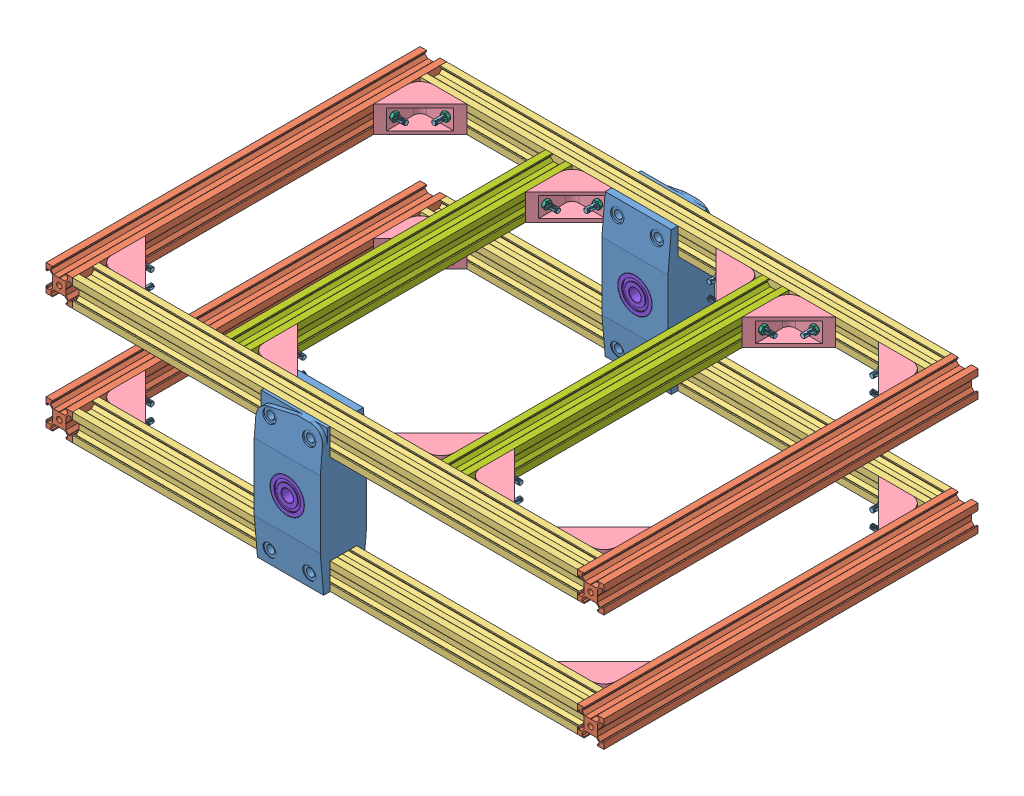
SolidWorks assembly Total Frame, configuration Default. Lengths in mm.
Overall size (422 108 298).
102 component instances, 8 part files, 22 mates.
Components (placement in the parent):
- rocker to body-1: rocker to body [Default] at (-21 0 131.5) size (50 108 35)
- Bottom Frame-1: Bottom Frame [Default] at (-340.2356 -200.3375 -193.6184) size (422 20 283) (flexible)
  - T-slot aluminium profiles(283)-2: T-slot aluminium profiles(283) [Default] at (139.2356 156.3375 52.1184) size (20 20 283)
  - T-slot aluminium profiles(382)-2: T-slot aluminium profiles(382) [Default] at (531.2356 156.3375 325.1184) x (0 0 1) z (-1 0 0) size (20 20 382)
  - T-slot aluminium profiles(382)-3: T-slot aluminium profiles(382) [Default] at (531.2356 156.3375 62.1184) x (0 0 1) z (-1 0 0) size (20 20 382)
  - T-slot aluminium profiles(283)-3: T-slot aluminium profiles(283) [Default] at (541.2356 156.3375 52.1184) size (20 20 283)
  - Connector and Nut-1: Connector and Nut [Default] at (495.0014 140.4658 271.3786) size (38.1 20 38.1) (flexible)
    - connector-1: connector [Default] at (36.2342 15.8717 43.7398) size (35.36 20 35.36)
    - T-bolt-1: T-bolt [Default] at (38.0779 15.8717 18.3844) x (-1 0 0) z (0 0 -1) size (17.8 12.7 9.5)
    - hexagon nut style 1_is-2: hexagon nut style 1_is [IS 1364-3 - M3-W-N] at (28.8342 15.8717 18.3844) x (0 0.996107 0.088148) z (-1 0 0) size (5.5 6.35 2.4)
    - T-bolt-2: T-bolt [Default] at (10.8788 15.8717 45.5835) x (0 0 -1) z (1 0 0) size (17.8 12.7 9.5)
    - hexagon nut style 1_is-3: hexagon nut style 1_is [IS 1364-3 - M3-W-N] at (10.8788 15.8717 36.3398) x (0.175203 0.984532 0) z (0 0 -1) size (5.5 6.35 2.4)
  - Connector and Nut-2: Connector and Nut [Default] at (487.4958 140.4658 108.3525) x (0 0 -1) z (1 0 0) size (38.1 20 38.1) (flexible)
    - connector-1: connector [Default] at (36.2342 15.8717 43.7398) size (35.36 20 35.36)
    - T-bolt-1: T-bolt [Default] at (38.0779 15.8717 18.3844) x (-1 0 0) z (0 0 -1) size (17.8 12.7 9.5)
    - hexagon nut style 1_is-2: hexagon nut style 1_is [IS 1364-3 - M3-W-N] at (28.8342 15.8717 18.3844) x (0 0.996107 0.088148) z (-1 0 0) size (5.5 6.35 2.4)
    - T-bolt-2: T-bolt [Default] at (10.8788 15.8717 45.5835) x (0 0 -1) z (1 0 0) size (17.8 12.7 9.5)
    - hexagon nut style 1_is-3: hexagon nut style 1_is [IS 1364-3 - M3-W-N] at (10.8788 15.8717 36.3398) x (0.175203 0.984532 0) z (0 0 -1) size (5.5 6.35 2.4)
  - Connector and Nut-3: Connector and Nut [Default] at (192.9754 140.4658 278.8842) x (0 0 1) z (-1 0 0) size (38.1 20 38.1) (flexible)
    - connector-1: connector [Default] at (36.2342 15.8717 43.7398) size (35.36 20 35.36)
    - T-bolt-1: T-bolt [Default] at (38.0779 15.8717 18.3844) x (-1 0 0) z (0 0 -1) size (17.8 12.7 9.5)
    - hexagon nut style 1_is-2: hexagon nut style 1_is [IS 1364-3 - M3-W-N] at (28.8342 15.8717 18.3844) x (0 0.996107 0.088148) z (-1 0 0) size (5.5 6.35 2.4)
    - T-bolt-2: T-bolt [Default] at (10.8788 15.8717 45.5835) x (0 0 -1) z (1 0 0) size (17.8 12.7 9.5)
    - hexagon nut style 1_is-3: hexagon nut style 1_is [IS 1364-3 - M3-W-N] at (10.8788 15.8717 36.3398) x (0.175203 0.984532 0) z (0 0 -1) size (5.5 6.35 2.4)
  - Connector and Nut-4: Connector and Nut [Default] at (185.4698 140.4658 115.8582) x (-1 0 0) z (0 0 -1) size (38.1 20 38.1) (flexible)
    - connector-1: connector [Default] at (36.2342 15.8717 43.7398) size (35.36 20 35.36)
    - T-bolt-1: T-bolt [Default] at (38.0779 15.8717 18.3844) x (-1 0 0) z (0 0 -1) size (17.8 12.7 9.5)
    - hexagon nut style 1_is-2: hexagon nut style 1_is [IS 1364-3 - M3-W-N] at (28.8342 15.8717 18.3844) x (0 0.996107 0.088148) z (-1 0 0) size (5.5 6.35 2.4)
    - T-bolt-2: T-bolt [Default] at (10.8788 15.8717 45.5835) x (0 0 -1) z (1 0 0) size (17.8 12.7 9.5)
    - hexagon nut style 1_is-3: hexagon nut style 1_is [IS 1364-3 - M3-W-N] at (10.8788 15.8717 36.3398) x (0.175203 0.984532 0) z (0 0 -1) size (5.5 6.35 2.4)
- Top Frame-1: Top Frame [Default] at (-340.2356 -112.3375 -193.6184) size (422 20 283) (flexible)
  - T-slot aluminium profiles(283)-2: T-slot aluminium profiles(283) [Default] at (139.2356 156.3375 52.1184) size (20 20 283)
  - T-slot aluminium profiles(382)-2: T-slot aluminium profiles(382) [Default] at (531.2356 156.3375 325.1184) x (0 0 1) z (-1 0 0) size (20 20 382)
  - T-slot aluminium profiles(382)-3: T-slot aluminium profiles(382) [Default] at (531.2356 156.3375 62.1184) x (0 0 1) z (-1 0 0) size (20 20 382)
  - T-slot aluminium profiles(283)-3: T-slot aluminium profiles(283) [Default] at (541.2356 156.3375 52.1184) size (20 20 283)
  - T-slot aluminium profiles(243)-1: T-slot aluminium profiles(243) [Default] at (418.2356 156.3375 72.1184) size (20 20 243)
  - T-slot aluminium profiles(243)-2: T-slot aluminium profiles(243) [Default] at (254.2356 156.3375 72.1184) size (20 20 243)
  - Connector and Nut-1: Connector and Nut [Default] at (495.0014 140.4658 271.3786) size (38.1 20 38.1) (flexible)
    - connector-1: connector [Default] at (36.2342 15.8717 43.7398) size (35.36 20 35.36)
    - T-bolt-1: T-bolt [Default] at (38.0779 15.8717 18.3844) x (-1 0 0) z (0 0 -1) size (17.8 12.7 9.5)
    - hexagon nut style 1_is-2: hexagon nut style 1_is [IS 1364-3 - M3-W-N] at (28.8342 15.8717 18.3844) x (0 0.996107 0.088148) z (-1 0 0) size (5.5 6.35 2.4)
    - T-bolt-2: T-bolt [Default] at (10.8788 15.8717 45.5835) x (0 0 -1) z (1 0 0) size (17.8 12.7 9.5)
    - hexagon nut style 1_is-3: hexagon nut style 1_is [IS 1364-3 - M3-W-N] at (10.8788 15.8717 36.3398) x (0.175203 0.984532 0) z (0 0 -1) size (5.5 6.35 2.4)
  - Connector and Nut-2: Connector and Nut [Default] at (487.4958 140.4658 108.3525) x (0 0 -1) z (1 0 0) size (38.1 20 38.1) (flexible)
    - connector-1: connector [Default] at (36.2342 15.8717 43.7398) size (35.36 20 35.36)
    - T-bolt-1: T-bolt [Default] at (38.0779 15.8717 18.3844) x (-1 0 0) z (0 0 -1) size (17.8 12.7 9.5)
    - hexagon nut style 1_is-2: hexagon nut style 1_is [IS 1364-3 - M3-W-N] at (28.8342 15.8717 18.3844) x (0 0.922855 0.385148) z (-1 0 0) size (5.5 6.35 2.4)
    - T-bolt-2: T-bolt [Default] at (10.8788 15.8717 45.5835) x (0 0 -1) z (1 0 0) size (17.8 12.7 9.5)
    - hexagon nut style 1_is-3: hexagon nut style 1_is [IS 1364-3 - M3-W-N] at (10.8788 15.8717 36.3398) x (0.207562 0.978222 0) z (0 0 -1) size (5.5 6.35 2.4)
  - Connector and Nut-3: Connector and Nut [Default] at (372.0014 140.4658 271.3786) size (38.1 20 38.1) (flexible)
    - connector-1: connector [Default] at (36.2342 15.8717 43.7398) size (35.36 20 35.36)
    - T-bolt-1: T-bolt [Default] at (38.0779 15.8717 18.3844) x (-1 0 0) z (0 0 -1) size (17.8 12.7 9.5)
    - hexagon nut style 1_is-2: hexagon nut style 1_is [IS 1364-3 - M3-W-N] at (28.8342 15.8717 18.3844) x (0 0.996107 0.088148) z (-1 0 0) size (5.5 6.35 2.4)
    - T-bolt-2: T-bolt [Default] at (10.8788 15.8717 45.5835) x (0 0 -1) z (1 0 0) size (17.8 12.7 9.5)
    - hexagon nut style 1_is-3: hexagon nut style 1_is [IS 1364-3 - M3-W-N] at (10.8788 15.8717 36.3398) x (0.175203 0.984532 0) z (0 0 -1) size (5.5 6.35 2.4)
  - Connector and Nut-4: Connector and Nut [Default] at (471.9754 140.4658 278.8842) x (0 0 1) z (-1 0 0) size (38.1 20 38.1) (flexible)
    - connector-1: connector [Default] at (36.2342 15.8717 43.7398) size (35.36 20 35.36)
    - T-bolt-1: T-bolt [Default] at (38.0779 15.8717 18.3844) x (-1 0 0) z (0 0 -1) size (17.8 12.7 9.5)
    - hexagon nut style 1_is-2: hexagon nut style 1_is [IS 1364-3 - M3-W-N] at (28.8342 15.8717 18.3844) x (0 0.996107 0.088148) z (-1 0 0) size (5.5 6.35 2.4)
    - T-bolt-2: T-bolt [Default] at (10.8788 15.8717 45.5835) x (0 0 -1) z (1 0 0) size (17.8 12.7 9.5)
    - hexagon nut style 1_is-3: hexagon nut style 1_is [IS 1364-3 - M3-W-N] at (10.8788 15.8717 36.3398) x (0.175203 0.984532 0) z (0 0 -1) size (5.5 6.35 2.4)
  - Connector and Nut-5: Connector and Nut [Default] at (192.9754 140.4658 278.8842) x (0 0 1) z (-1 0 0) size (38.1 20 38.1) (flexible)
    - connector-1: connector [Default] at (36.2342 15.8717 43.7398) size (35.36 20 35.36)
    - T-bolt-1: T-bolt [Default] at (38.0779 15.8717 18.3844) x (-1 0 0) z (0 0 -1) size (17.8 12.7 9.5)
    - hexagon nut style 1_is-2: hexagon nut style 1_is [IS 1364-3 - M3-W-N] at (28.8342 15.8717 18.3844) x (0 0.996107 0.088148) z (-1 0 0) size (5.5 6.35 2.4)
    - T-bolt-2: T-bolt [Default] at (10.8788 15.8717 45.5835) x (0 0 -1) z (1 0 0) size (17.8 12.7 9.5)
    - hexagon nut style 1_is-3: hexagon nut style 1_is [IS 1364-3 - M3-W-N] at (10.8788 15.8717 36.3398) x (0.175203 0.984532 0) z (0 0 -1) size (5.5 6.35 2.4)
  - Connector and Nut-6: Connector and Nut [Default] at (364.4958 140.4658 108.3525) x (0 0 -1) z (1 0 0) size (38.1 20 38.1) (flexible)
    - connector-1: connector [Default] at (36.2342 15.8717 43.7398) size (35.36 20 35.36)
    - T-bolt-1: T-bolt [Default] at (38.0779 15.8717 18.3844) x (-1 0 0) z (0 0 -1) size (17.8 12.7 9.5)
    - hexagon nut style 1_is-2: hexagon nut style 1_is [IS 1364-3 - M3-W-N] at (28.8342 15.8717 18.3844) x (0 0.996107 0.088148) z (-1 0 0) size (5.5 6.35 2.4)
    - T-bolt-2: T-bolt [Default] at (10.8788 15.8717 45.5835) x (0 0 -1) z (1 0 0) size (17.8 12.7 9.5)
    - hexagon nut style 1_is-3: hexagon nut style 1_is [IS 1364-3 - M3-W-N] at (10.8788 15.8717 36.3398) x (0.175203 0.984532 0) z (0 0 -1) size (5.5 6.35 2.4)
  - Connector and Nut-7: Connector and Nut [Default] at (464.4698 140.4658 115.8582) x (-1 0 0) z (0 0 -1) size (38.1 20 38.1) (flexible)
    - connector-1: connector [Default] at (36.2342 15.8717 43.7398) size (35.36 20 35.36)
    - T-bolt-1: T-bolt [Default] at (38.0779 15.8717 18.3844) x (-1 0 0) z (0 0 -1) size (17.8 12.7 9.5)
    - hexagon nut style 1_is-2: hexagon nut style 1_is [IS 1364-3 - M3-W-N] at (28.8342 15.8717 18.3844) x (0 0.996107 0.088148) z (-1 0 0) size (5.5 6.35 2.4)
    - T-bolt-2: T-bolt [Default] at (10.8788 15.8717 45.5835) x (0 0 -1) z (1 0 0) size (17.8 12.7 9.5)
    - hexagon nut style 1_is-3: hexagon nut style 1_is [IS 1364-3 - M3-W-N] at (10.8788 15.8717 36.3398) x (0.175203 0.984532 0) z (0 0 -1) size (5.5 6.35 2.4)
  - Connector and Nut-8: Connector and Nut [Default] at (185.4698 140.4658 115.8582) x (-1 0 0) z (0 0 -1) size (38.1 20 38.1) (flexible)
    - connector-1: connector [Default] at (36.2342 15.8717 43.7398) size (35.36 20 35.36)
    - T-bolt-1: T-bolt [Default] at (38.0779 15.8717 18.3844) x (-1 0 0) z (0 0 -1) size (17.8 12.7 9.5)
    - hexagon nut style 1_is-2: hexagon nut style 1_is [IS 1364-3 - M3-W-N] at (28.8342 15.8717 18.3844) x (0 0.646881 -0.762591) z (-1 0 0) size (5.5 6.35 2.4)
    - T-bolt-2: T-bolt [Default] at (10.8788 15.8717 45.5835) x (0 0 -1) z (1 0 0) size (17.8 12.7 9.5)
    - hexagon nut style 1_is-3: hexagon nut style 1_is [IS 1364-3 - M3-W-N] at (10.8788 15.8717 36.3398) x (0.175203 0.984532 0) z (0 0 -1) size (5.5 6.35 2.4)
  - Connector and Nut-9: Connector and Nut [Default] at (307.9754 140.4658 278.8842) x (0 0 1) z (-1 0 0) size (38.1 20 38.1) (flexible)
    - connector-1: connector [Default] at (36.2342 15.8717 43.7398) size (35.36 20 35.36)
    - T-bolt-1: T-bolt [Default] at (38.0779 15.8717 18.3844) x (-1 0 0) z (0 0 -1) size (17.8 12.7 9.5)
    - hexagon nut style 1_is-2: hexagon nut style 1_is [IS 1364-3 - M3-W-N] at (28.8342 15.8717 18.3844) x (0 0.977522 0.210833) z (-1 0 0) size (5.5 6.35 2.4)
    - T-bolt-2: T-bolt [Default] at (10.8788 15.8717 45.5835) x (0 0 -1) z (1 0 0) size (17.8 12.7 9.5)
    - hexagon nut style 1_is-3: hexagon nut style 1_is [IS 1364-3 - M3-W-N] at (10.8788 15.8717 36.3398) x (0.179382 0.98378 0) z (0 0 -1) size (5.5 6.35 2.4)
  - Connector and Nut-10: Connector and Nut [Default] at (300.4698 140.4658 115.8582) x (-1 0 0) z (0 0 -1) size (38.1 20 38.1) (flexible)
    - connector-1: connector [Default] at (36.2342 15.8717 43.7398) size (35.36 20 35.36)
    - T-bolt-1: T-bolt [Default] at (38.0779 15.8717 18.3844) x (-1 0 0) z (0 0 -1) size (17.8 12.7 9.5)
    - hexagon nut style 1_is-2: hexagon nut style 1_is [IS 1364-3 - M3-W-N] at (28.8342 15.8717 18.3844) x (0 0.997259 0.073993) z (-1 0 0) size (5.5 6.35 2.4)
    - T-bolt-2: T-bolt [Default] at (10.8788 15.8717 45.5835) x (0 0 -1) z (1 0 0) size (17.8 12.7 9.5)
    - hexagon nut style 1_is-3: hexagon nut style 1_is [IS 1364-3 - M3-W-N] at (10.8788 15.8717 36.3398) x (0.103111 0.99467 0) z (0 0 -1) size (5.5 6.35 2.4)
- double row radial ball bearing_is-1: double row radial ball bearing_is [IS 6456 DR - 02-9-S] at (-21 0 145) x (0.998062 0.062228 0) z (0 0 1) size (26 26 8)
- double row radial ball bearing_is-2: double row radial ball bearing_is [IS 6456 DR - 02-9-S] at (-21 0 -145) x (0.962516 -0.271223 0) z (0 0 1) size (26 26 8)
- double row radial ball bearing_is-3: double row radial ball bearing_is [IS 6456 DR - 02-9-S] at (-21 0 -118) x (0.998062 0.062228 0) z (0 0 1) size (26 26 8)
- double row radial ball bearing_is-4: double row radial ball bearing_is [IS 6456 DR - 02-9-S] at (-21 0 118) x (0.998062 0.062228 0) z (0 0 1) size (26 26 8)
- rocker to body-3: rocker to body [RHS] at (-21 0 -166.5) size (50 108 35)
Mates (geometry in assembly coordinates):
- Coincident1: coincident: plane of rocker to body-1 through (4 34 141.5) normal (0 1 0); plane of Top Frame-1/T-slot aluminium profiles(382)-2 through (-191 34 131.5) normal (0 -1 0)
- Coincident2: coincident: plane of rocker to body-1 through (4 54 149) normal (0 1 0); plane of Top Frame-1/T-slot aluminium profiles(382)-2 through (-191 54 131.5) normal (0 1 0)
- Coincident3: coincident: plane of rocker to body-1 through (4 -34 141.5) normal (0 -1 0); plane of Bottom Frame-1/T-slot aluminium profiles(382)-2 through (-191 -34 131.5) normal (0 1 0)
- Coincident4: coincident: plane of rocker to body-1 through (-21 0 141.5) normal (0 0 -1); plane of Bottom Frame-1/T-slot aluminium profiles(382)-2 through (-191 -44 141.5) normal (0 0 1)
- Coincident5: coincident: plane of rocker to body-1 through (-21 0 141.5) normal (0 0 -1); plane of Top Frame-1/T-slot aluminium profiles(382)-2 through (-191 44 141.5) normal (0 0 1)
- Coincident6: coincident: plane of Bottom Frame-1/T-slot aluminium profiles(283)-2 through (-211 -44 141.5) normal (-1 0 0); plane of Top Frame-1/T-slot aluminium profiles(283)-2 through (-211 44 141.5) normal (-1 0 0)
- Concentric1: concentric: cylinder of rocker to body-1 through (-21 0 113.999) axis (0 0 1) radius 13; cylinder of double row radial ball bearing_is-1 through (-21 0 195.3916) axis (0 0 1) radius 13
- Coincident11: coincident: plane of rocker to body-1 through (-21 0 149) normal (0 0 1); plane of double row radial ball bearing_is-1 through (-21.809 12.9748 149) normal (0 0 1)
- Concentric4: concentric: cylinder of rocker to body-1 through (-21 0 113.999) axis (0 0 1) radius 13; cylinder of double row radial ball bearing_is-4 through (-21 0 168.3916) axis (0 0 1) radius 13
- Coincident14: coincident: plane of rocker to body-1 through (-21 0 114) normal (0 0 -1); plane of double row radial ball bearing_is-4 through (-21.28 4.4913 114) normal (0 0 -1)
- Parallel1: parallel: plane of rocker to body-1 through (-46 -34 141.5) normal (-1 0 0); plane of rocker to body-3 through (-46 -34 -141.5) normal (-1 0 0)
- Coincident15: coincident: plane of Top Frame-1/T-slot aluminium profiles(382)-3 through (-191 34 -131.5) normal (0 -1 0); plane of rocker to body-3 through (4 34 -141.5) normal (0 1 0)
- Coincident16: coincident: plane of Top Frame-1/T-slot aluminium profiles(382)-3 through (-191 44 -141.5) normal (0 0 -1); plane of rocker to body-3 through (-21 0 -141.5) normal (0 0 1)
- Coincident17: coincident: plane of rocker to body-1 through (-46 -34 141.5) normal (-1 0 0); plane of rocker to body-3 through (-46 -34 -141.5) normal (-1 0 0)
- Concentric5: concentric: cylinder of double row radial ball bearing_is-2 through (-21 0 -94.6084) axis (0 0 1) radius 13; cylinder of rocker to body-3 through (-21 0 -113.999) axis (0 0 -1) radius 13
- Coincident18: coincident: plane of double row radial ball bearing_is-2 through (-17.4741 12.5127 -149) normal (0 0 -1); plane of rocker to body-3 through (-21 0 -149) normal (0 0 -1)
- Concentric6: concentric: cylinder of double row radial ball bearing_is-3 through (-21 0 -67.6084) axis (0 0 1) radius 13; cylinder of rocker to body-3 through (-21 0 -113.999) axis (0 0 -1) radius 13
- Coincident19: coincident: plane of double row radial ball bearing_is-3 through (-21.809 12.9748 -114) normal (0 0 1); plane of rocker to body-3 through (-21 0 -114) normal (0 0 1)
- Distance1: distance = 30 mm: plane of rocker to body-1 through (-46 -34 141.5) normal (-1 0 0); plane of Top Frame-1/T-slot aluminium profiles(243)-2 through (-76 44 121.5) normal (1 0 0)
- Symmetric3: symmetric: plane of Top Frame-1/T-slot aluminium profiles(283)-2 through (-211 44 141.5) normal (-1 0 0); plane of Top Frame-1/T-slot aluminium profiles(283)-3 through (211 44 141.5) normal (1 0 0); plane of assembly
- Symmetric4: symmetric: plane of Bottom Frame-1/T-slot aluminium profiles(283)-3 through (201 -54 141.5) normal (0 -1 0); plane of Top Frame-1/T-slot aluminium profiles(283)-3 through (201 54 141.5) normal (0 1 0)
- Symmetric5: symmetric: plane of Top Frame-1/T-slot aluminium profiles(382)-2 through (-191 44 141.5) normal (0 0 1); plane of Top Frame-1/T-slot aluminium profiles(382)-3 through (-191 44 -141.5) normal (0 0 -1); plane of assembly
